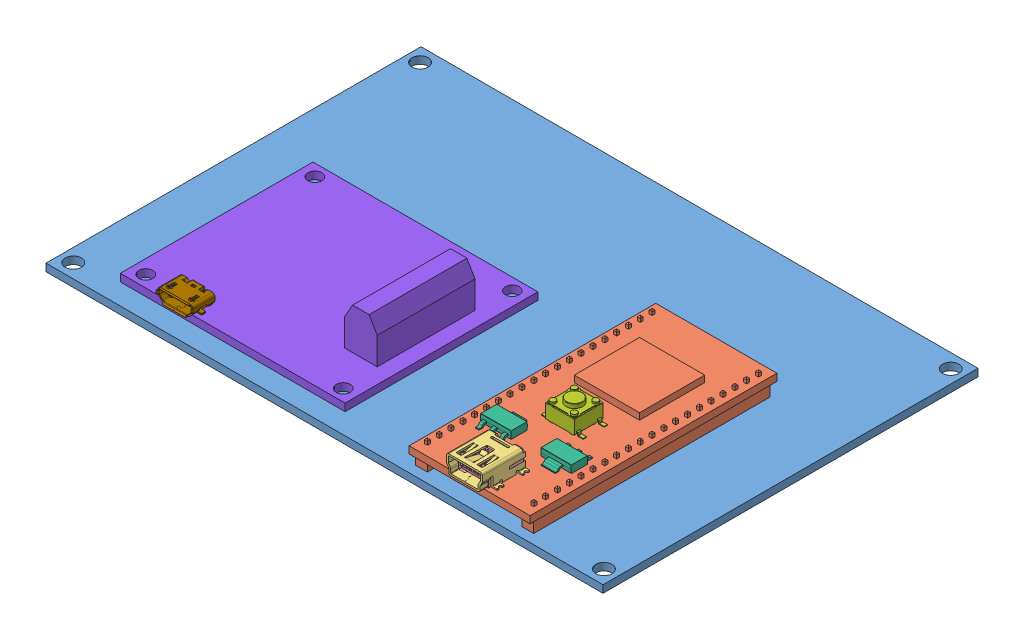
SolidWorks assembly electronics, configuration Default. Lengths in mm.
Overall size (119.65 18.49 80.68).
17 component instances, 9 part files, 6 mates.
Components (placement in the parent):
- protoboard-1: protoboard [Default] at origin size (119.65 1.6 80.55)
- mbed_NXP_LPC1768-1: mbed_NXP_LPC1768 [Default] at (30.165 4.1 12.775) size (26 10.32 54.13)
  - mbed_NXP_LPC1768-1: mbed_NXP_LPC1768 [Default] at origin size (26 7.42 53)
  - usb_mini_b-1: usb_mini_b [Default] at (0 3.474 23) x (-1 0 0) z (0 -1 0) size (9.6 9.25 4.91)
    - Shielding-1: Shielding [Default] at origin size (9.6 9.25 4.01)
    - Insulator-1: Insulator [Default] at (0 2.75 0.2) size (7.7 7.5 4.5)
    - Pin_1-1: Pin_1 [Default] at (-1.6 2.225 0.575) size (0.4 7.85 3.02)
    - Pin_1-2: Pin_1 [Default] at (-0.8 2.225 0.575) size (0.4 7.85 3.02)
    - Pin_1-3: Pin_1 [Default] at (0 2.225 0.575) size (0.4 7.85 3.02)
    - Pin_1-4: Pin_1 [Default] at (0.8 2.225 0.575) size (0.4 7.85 3.02)
    - Pin_1-5: Pin_1 [Default] at (1.6 2.225 0.575) size (0.4 7.85 3.02)
  - SOT-223-1: SOT-223 [Default] at (-6.8 -6.9808 24) x (0 0 1) z (-1 0 0) size (6.89 1.7 6.5)
  - SOT-223-2: SOT-223 [Default] at (6.7 -6.9808 1.2) x (0 0 -1) z (1 0 0) size (6.89 1.7 6.5)
  - Tact_Sw_SMD_6x6mm-1: Tact_Sw_SMD_6x6mm [Default] at (0 1.524 4) x (1 0 0) z (0 1 0) size (9 6.2 4.3)
- motor-controller-1: motor-controller [Default] at (-21.675 4.14 17.625) x (0 0 -1) z (1 0 0) size (42.6 13.95 48.3)
  - motor-controller-pcb-1: motor-controller-pcb [Default] at origin size (41.4 13.95 48.3)
  - micro-usb-connector-1: micro-usb-connector [Default] at (-19.12 2.825 -11.5) x (0 0 1) z (-1 0 0) size (7.98 2.94 5.43)
Mates (geometry in assembly coordinates):
- Coincident1: coincident: plane of protoboard-1 through (0 1.6 0) normal (0 1 0); plane of mbed_NXP_LPC1768-1/mbed_NXP_LPC1768-1 through (30.165 1.6 12.775) normal (0 -1 0)
- Distance1: distance = 1 mm: plane of mbed_NXP_LPC1768-1/mbed_NXP_LPC1768-1 through (17.165 5.624 39.275) normal (0 0 1); plane of protoboard-1 through (-59.825 1.6 40.275) normal (0 0 1)
- Distance2: distance = 16.66 mm: plane of mbed_NXP_LPC1768-1/mbed_NXP_LPC1768-1 through (43.165 5.624 39.275) normal (1 0 0); plane of protoboard-1 through (59.825 1.6 -40.275) normal (1 0 0)
- Distance3: distance = 2.54 mm: plane of motor-controller-1/motor-controller-pcb-1 through (-21.675 4.14 17.625) normal (0 -1 0); plane of protoboard-1 through (0 1.6 0) normal (0 1 0)
- Distance4: distance = 1.95 mm: plane of motor-controller-1/motor-controller-pcb-1 through (-45.825 5.74 38.325) normal (0 0 1); plane of protoboard-1 through (-59.825 1.6 40.275) normal (0 0 1)
- Distance5: distance = 14 mm: plane of motor-controller-1/motor-controller-pcb-1 through (-45.825 5.74 -3.075) normal (-1 0 0); plane of protoboard-1 through (-59.825 1.6 -40.275) normal (-1 0 0)
